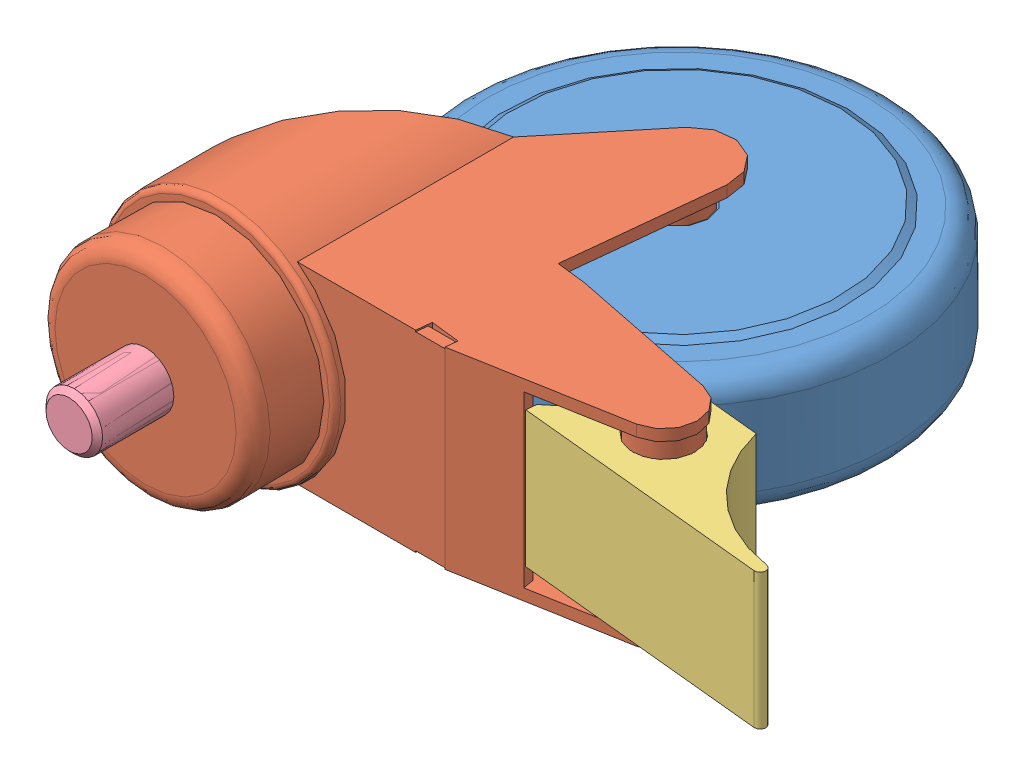
SolidWorks assembly 21.1120 WHEEL WITH BRAKE, configuration Default. Lengths in mm.
Overall size (118.74 42 113.5).
5 component instances, 5 part files, 10 mates.
Components (placement in the parent):
- 21.1120 WHEEL 75mm-1: 21.1120 WHEEL 75mm [Default] at origin size (75 23.5 75)
- 21.1120 FORK-1: 21.1120 FORK [Default] at (-31.5 0 62.5) size (92.98 42 72)
- 21.1120 BRAKE-1: 21.1120 BRAKE [Default] at (-28.5589 0 56.3657) x (0.995113 0 0.098744) z (-0.098744 0 0.995113) size (45.98 24 19)
- SHCS M10X30 LOW HEAD DIN 7984-1: SHCS M10X30 LOW HEAD DIN 7984 [Default] at (-31.5 0 46) x (0 0 1) z (-1 0 0) size (36 16 16)
- WAHSER M10 ROUND DIN 125-1A FOR WHEEL-1: WAHSER M10 ROUND DIN 125-1A FOR WHEEL [Default] at (-31.5 0 46) x (0 0 1) z (-1 0 0) size (2 20 20)
Mates (geometry in assembly coordinates):
- Concentric1: concentric: cylinder of 21.1120 WHEEL 75mm-1 through (0 0 0) axis (0 1 0) radius 4; cylinder of 21.1120 FORK-1 through (0 15 0) axis (0 -1 0) radius 5
- Coincident1: coincident: plane of 21.1120 WHEEL 75mm-1 through (0 0 0) normal (0 1 0); plane of 21.1120 FORK-1 through (-31.5 0 62.5) normal (0 1 0)
- Angle1: planar angle = 0 rad: plane of 21.1120 FORK-1 through (-23.5 0 62.5) normal (0 0 1); plane of assembly through (0 0 0) normal (0 0 1)
- Concentric2: concentric: cylinder of 21.1120 FORK-1 through (34.5226 0 36.99) axis (0 1 0) radius 5.5; cylinder of 21.1120 BRAKE-1 through (34.5226 0 36.99) axis (0 -1 0) radius 5.5
- Coincident3: coincident: plane of 21.1120 FORK-1 through (-31.5 0 62.5) normal (0 1 0); plane of 21.1120 BRAKE-1
- Coincident4: coincident: plane of 21.1120 FORK-1 through (18.6839 16.75 45.8802) normal (0.984274 0 -0.17665); line of 21.1120 BRAKE-1 through (18.6085 12 45.46) axis (0 -1 0)
- Concentric3: concentric: cylinder of SHCS M10X30 LOW HEAD DIN 7984-1 through (-31.5 0 21.0387) axis (0 0 1) radius 5; cylinder of WAHSER M10 ROUND DIN 125-1A FOR WHEEL-1 through (-31.5 0 3.7887) axis (0 0 1) radius 5.25
- Coincident5: coincident: plane of SHCS M10X30 LOW HEAD DIN 7984-1 through (-31.5 6.5 46) normal (0 0 1); plane of WAHSER M10 ROUND DIN 125-1A FOR WHEEL-1 through (-31.5 0 46) normal (0 0 -1)
- Concentric4: concentric: cylinder of 21.1120 FORK-1 through (-31.5 0 47.5) axis (0 0 -1) radius 5; cylinder of SHCS M10X30 LOW HEAD DIN 7984-1 through (-31.5 0 21.0387) axis (0 0 1) radius 5
- Coincident6: coincident: plane of 21.1120 FORK-1 through (-31.5 0 48) normal (0 0 -1); plane of WAHSER M10 ROUND DIN 125-1A FOR WHEEL-1 through (-31.5 0 48) normal (0 0 1)
